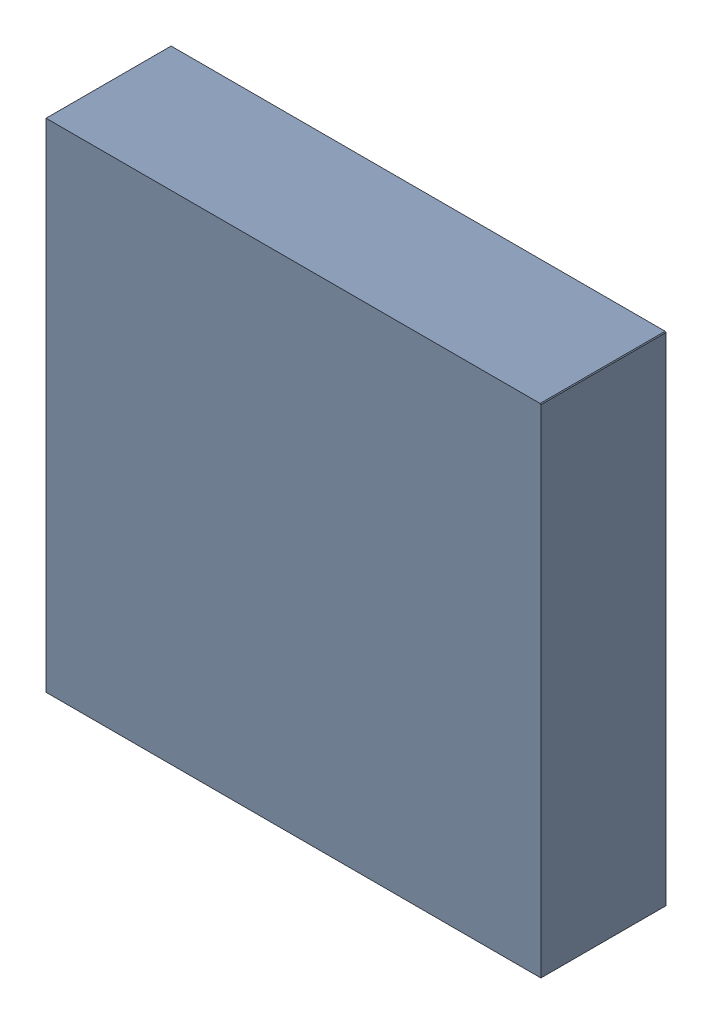
SolidWorks assembly U4, configuration ﾃﾞﾌｫﾙﾄ. Lengths in mm.
Overall size (3.17 3.19 0.82).
4 component instances, 2 part files, 0 mates.
Components (placement in the parent):
- 6641442208-1: 6641442208 [ﾃﾞﾌｫﾙﾄ] at (4.4325 4.57 -2.7339) size (3.17 3.19 0.81)
  - Extruded-19-1: Extruded-19 [ﾃﾞﾌｫﾙﾄ] at origin size (3.17 3.19 0.81)
- 6641440128-1: 6641440128 [ﾃﾞﾌｫﾙﾄ] at (5.7448 3.3092 -2.7339) x (0 1 0) z (0 0 -1) size (0.2 0.2 0.01)
  - Cylinder-23-1: Cylinder-23 [ﾃﾞﾌｫﾙﾄ] at origin size (0.2 0.2 0.01)
